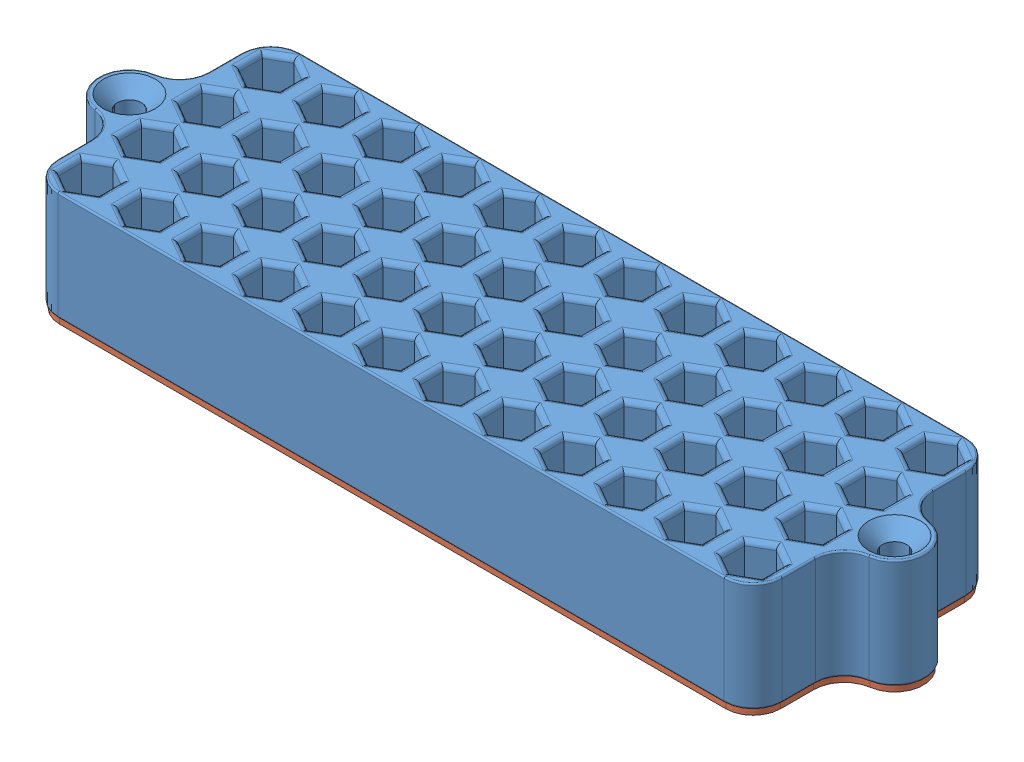
SolidWorks assembly Assem1, configuration Default. Lengths in mm.
Overall size (135.71 18.89 39.72).
2 component instances, 2 part files, 4 mates.
Components (placement in the parent):
- just bits hex-1: just bits hex [Default] at origin size (135.71 17.89 39.72)
- Part1^bit holder hex bottom cover-1: Part1^bit holder hex bottom cover [Default] at (0 -3.6 0) x (-1 0 0) z (0 -1 0) size (135.2 39.21 1) (virtual)
Mates (geometry in assembly coordinates):
- InPlace1: in place: plane of just bits hex-1 through (0 -3.6 0) normal (0 -1 0); plane of Part1^bit holder hex bottom cover-1 through (0 -3.6 0) normal (0 -1 0); moOrthogonalPlaneRef_w of just bits hex-1 through (0 -3.6 0) normal (0 -1 0); plane of Part1^bit holder hex bottom cover-1 through (0 -3.6 0) normal (0 0 -1); plane of just bits hex-1 through (0 -3.6 0) normal (0 -1 0); plane of Part1^bit holder hex bottom cover-1 through (0 -3.6 0) normal (-1 0 0); plane of just bits hex-1 through (0 -3.6 0) normal (0 -1 0); unknown of Part1^bit holder hex bottom cover-1
- Coincident1: coincident aligned: plane of ?; plane of ?
- Coincident2: coincident aligned: moOrthogonalPlaneRef_w of just bits hex-1 through (0 -3.6 0) normal (0 0 -1); plane of Part1^Assem1-1 through (0 -3.6 0) normal (0 0 -1)
- Coincident3: coincident anti-aligned: moOrthogonalPlaneRef_w of just bits hex-1 through (0 -3.6 0) normal (1 0 0); plane of Part1^Assem1-1 through (0 -3.6 0) normal (-1 0 0)
